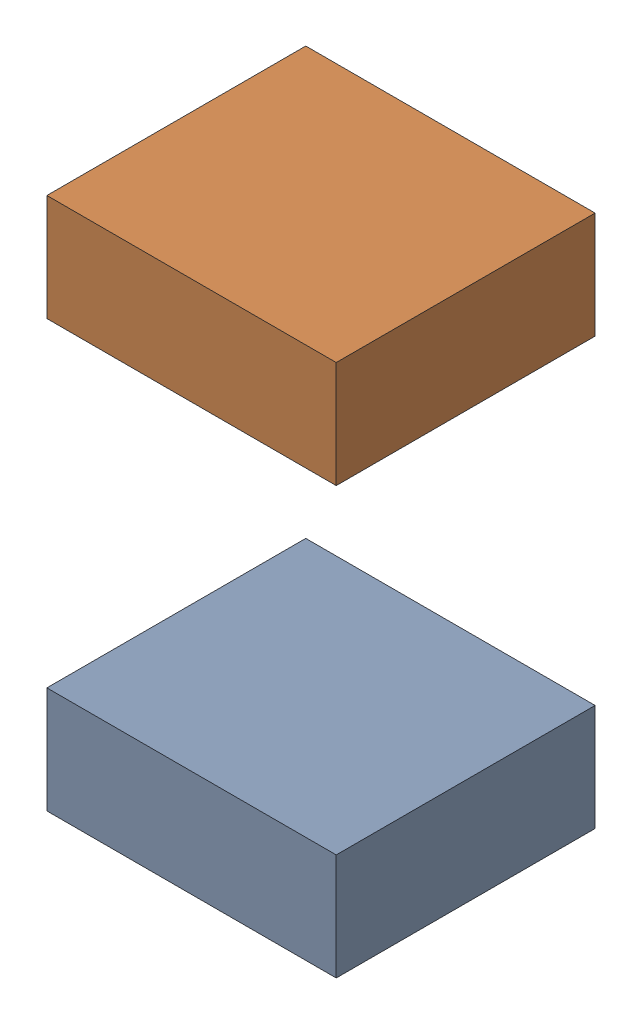
SolidWorks assembly C3, configuration 默认. Lengths in mm.
Overall size (0.95 1.75 0.85).
5 component instances, 1 part files, 0 mates.
Components (placement in the parent):
- 6241791616-1: 6241791616 [默认] at (11.557 16.891 0) (suppressed, hidden)
- 6241792176-1: 6241792176 [默认] at (11.557 16.191 0) size (0.95 0.35 0.85)
  - Extruded-1-1: Extruded-1 [默认] at origin size (0.95 0.35 0.85)
- 6241792176-2: 6241792176 [默认] at (11.557 17.591 0) size (0.95 0.35 0.85)
  - Extruded-1-1: Extruded-1 [默认] at origin size (0.95 0.35 0.85)
